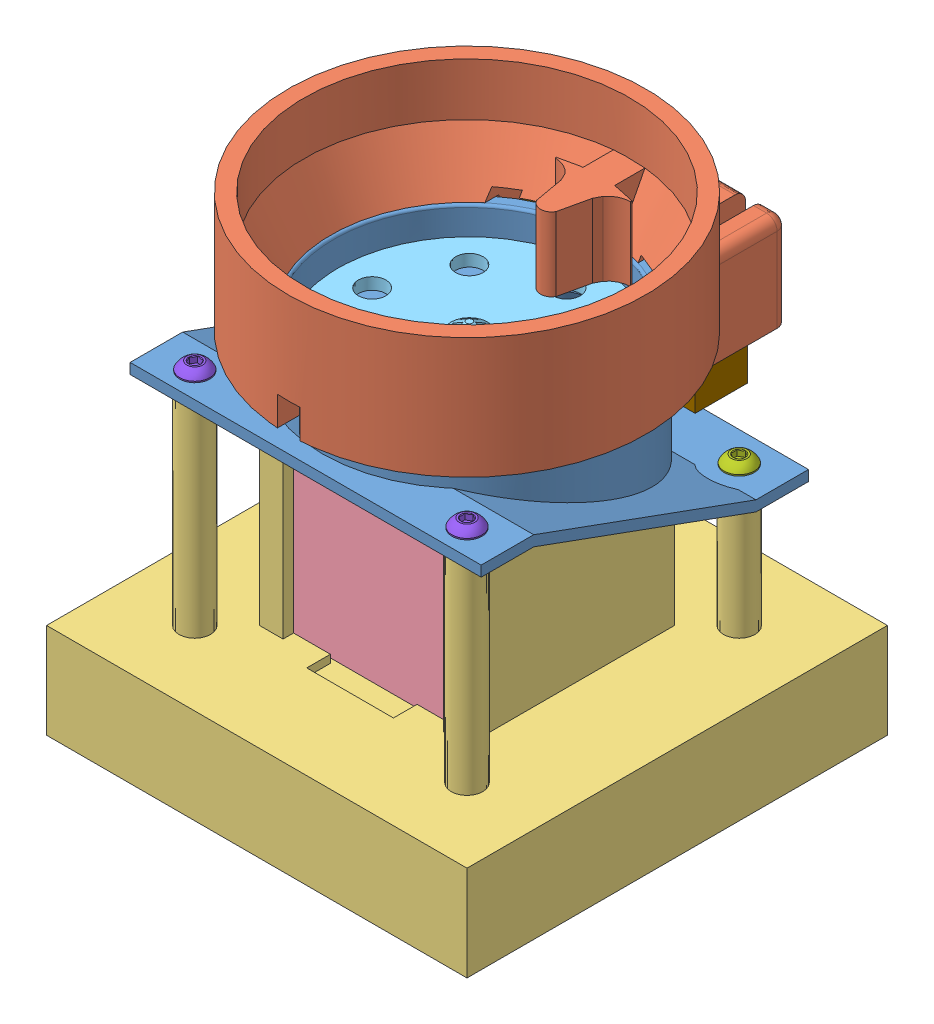
SolidWorks assembly FinalFeeder, configuration Default. Lengths in mm.
Overall size (80.53 89.55 87.61).
15 component instances, 9 part files, 34 mates.
Components (placement in the parent):
- Base V7-1: Base V7 [Default] at (6.73 27.5467 69.4591) size (66.8 28.84 76.98)
- Lid V5-1: Lid V5 [Default] at (6.73 62.8867 69.4591) x (-0.164094 0 -0.986445) z (0.986445 0 -0.164094) size (76.61 31 68.01)
- Motor Base V3-1: Motor Base V3 [Default] at (6.73 10.4376 69.4591) size (80 58.1 80)
- MotorModel-1: MotorModel [Default] at (6.73 12.9376 69.0091) size (34.6 49.4 34.6)
- Rotor V10-1: Rotor V10 [Default] at (6.73 60.8376 69.0091) x (0 0 1) z (-1 0 0) size (50 6 50)
- 90695A033 (Nut M3 thread)-1: 90695A033 (Nut M3 thread) [90695A033] at (-19.17 9.5376 95.3591) x (0.834067 0 -0.551664) z (0.551664 0 0.834067) size (5.5 2.19 6.35)
- 92095A201 (35mm lg M3 thread)-1: 92095A201 (35mm lg M3 thread) [92095A201] at (32.63 42.6967 43.5591) x (1 0 0) z (0 1 0) size (5.7 5.7 37.11)
- 92095A475 (50mm lg M3 thread)-1: 92095A475 (50mm lg M3 thread) [92095A475] at (-19.17 58.0876 95.3591) x (-0.089879 0 0.995953) z (0 1 0) size (5.7 5.7 52.2)
- 90695A033 (Nut M3 thread)-2: 90695A033 (Nut M3 thread) [90695A033] at (-19.17 9.5376 43.5591) x (0.598357 0 0.80123) z (-0.80123 0 0.598357) size (5.5 2.19 6.35)
- 92095A201 (35mm lg M3 thread)-2: 92095A201 (35mm lg M3 thread) [92095A201] at (-19.17 42.6967 43.5591) x (1 0 0) z (0 1 0) size (5.7 5.7 37.11)
- 92095A475 (50mm lg M3 thread)-2: 92095A475 (50mm lg M3 thread) [92095A475] at (32.63 58.0876 95.3591) x (1 0 0) z (0 1 0) size (5.7 5.7 52.2)
- 90695A033 (Nut M3 thread)-3: 90695A033 (Nut M3 thread) [90695A033] at (32.63 9.5376 95.3591) x (0.857215 0 -0.514959) z (0.514959 0 0.857215) size (5.5 2.19 6.35)
- 90695A033 (Nut M3 thread)-4: 90695A033 (Nut M3 thread) [90695A033] at (32.63 9.5376 43.5591) size (5.5 2.19 6.35)
- BreakBeam-1: BreakBeam [Default] at (-9.72 64.1316 32.5016) x (0 0 1) z (1 0 0) size (10 20 11)
- BreakBeam-2: BreakBeam [Default] at (23.18 64.1316 42.5016) x (0 0 -1) z (-1 0 0) size (10 20 11)
Mates (geometry in assembly coordinates):
- Coincident1: coincident anti-aligned: plane of Motor Base V3-1 through (6.73 12.9376 69.4591) normal (0 1 0); plane of MotorModel-1 through (6.73 12.9376 69.0091) normal (0 -1 0)
- Coincident3: coincident anti-aligned: plane of Motor Base V3-1 through (-11.02 12.9376 51.7091) normal (0 0 1); plane of MotorModel-1 through (-10.57 41.3376 51.7091) normal (0 0 -1)
- Concentric1: concentric aligned: cylinder of Base V7-1 through (-19.17 39.0467 43.5591) axis (0 -1 0) radius 1.75; cylinder of Motor Base V3-1 through (-19.17 54.4376 43.5591) axis (0 -1 0) radius 1.75
- Coincident4: coincident anti-aligned: plane of Base V7-1 through (40.13 54.4376 90.164) normal (0 -1 0); plane of Motor Base V3-1 through (32.63 54.4376 95.3591) normal (0 1 0)
- Concentric2: concentric aligned: cylinder of Base V7-1 through (32.63 39.0467 95.3591) axis (0 -1 0) radius 1.75; cylinder of Motor Base V3-1 through (32.63 54.4376 95.3591) axis (0 -1 0) radius 1.75
- Distance1: distance = 0.45 mm anti-aligned: plane of MotorModel-1 through (-10.57 41.3376 86.3091) normal (-1 0 0); plane of Motor Base V3-1 through (-11.02 12.9376 87.2091) normal (1 0 0)
- Parallel1: parallel aligned: plane of Lid V5-1 through (-14.27 -1.0757 29.4552) normal (0 0 -1); plane of Motor Base V3-1 through (-33.27 14.4376 29.4591) normal (0 0 -1)
- Concentric3: concentric aligned: circle of Base V7-1; circle of Lid V5-1
- Coincident8: coincident anti-aligned: plane of MotorModel-1 through (5.1052 62.3376 70.9091) normal (0 0 1); plane of Rotor V10-1 through (5.0293 70.8376 70.9091) normal (0 0 -1)
- Concentric4: concentric aligned: cylinder of MotorModel-1 through (6.73 62.3376 69.0091) axis (0 -1 0) radius 2.5; cylinder of Rotor V10-1 through (6.73 70.8376 69.0091) axis (0 -1 0) radius 2.55
- Coincident9: coincident anti-aligned: plane of MotorModel-1 through (6.73 62.3376 69.0091) normal (0 1 0); plane of Rotor V10-1 through (6.73 62.3376 69.0091) normal (0 -1 0)
- Concentric5: concentric anti-aligned: cylinder of Motor Base V3-1 through (-19.17 54.4376 95.3591) axis (0 -1 0) radius 1.75; circle of 92095A475 (50mm lg M3 thread)-1
- Concentric7: concentric aligned: circle of Motor Base V3-1; circle of 92095A475 (50mm lg M3 thread)-2
- Concentric8: concentric aligned: circle of Motor Base V3-1; circle of 92095A201 (35mm lg M3 thread)-1
- Concentric9: concentric aligned: circle of Motor Base V3-1; circle of 92095A201 (35mm lg M3 thread)-2
- Coincident12: coincident anti-aligned: plane of 92095A475 (50mm lg M3 thread)-2 through (32.63 56.4376 98.2091) normal (0 -1 0); plane of Base V7-1 through (40.13 56.4376 90.164) normal (0 1 0)
- Coincident13: coincident anti-aligned: plane of Base V7-1 through (40.13 56.4376 90.164) normal (0 1 0); plane of 92095A475 (50mm lg M3 thread)-1 through (-22.0085 56.4376 95.1029) normal (0 -1 0)
- Coincident15: coincident anti-aligned: plane of Base V7-1 through (40.13 41.0467 37.8778) normal (0 1 0); plane of 92095A201 (35mm lg M3 thread)-1 through (32.63 41.0467 46.4091) normal (0 -1 0)
- Coincident16: coincident anti-aligned: plane of Base V7-1 through (40.13 41.0467 37.8778) normal (0 1 0); plane of 92095A201 (35mm lg M3 thread)-2 through (-19.17 41.0467 46.4091) normal (0 -1 0)
- Concentric10: concentric aligned: circle of Motor Base V3-1; circle of 90695A033 (Nut M3 thread)-1
- Concentric11: concentric aligned: circle of Motor Base V3-1; circle of 90695A033 (Nut M3 thread)-2
- Concentric12: concentric aligned: circle of Motor Base V3-1; circle of 90695A033 (Nut M3 thread)-3
- Concentric13: concentric aligned: circle of Motor Base V3-1; circle of 90695A033 (Nut M3 thread)-4
- Coincident17: coincident anti-aligned: plane of Motor Base V3-1 through (6.73 10.4376 69.4591) normal (0 -1 0); plane of 90695A033 (Nut M3 thread)-4 through (29.88 10.4376 41.9714) normal (0 1 0)
- Coincident18: coincident anti-aligned: plane of Motor Base V3-1 through (6.73 10.4376 69.4591) normal (0 -1 0); plane of 90695A033 (Nut M3 thread)-2 through (-19.5433 10.4376 40.4057) normal (0 1 0)
- Coincident19: coincident anti-aligned: plane of Motor Base V3-1 through (6.73 10.4376 69.4591) normal (0 -1 0); plane of 90695A033 (Nut M3 thread)-1 through (-22.3396 10.4376 95.5519) normal (0 1 0)
- Coincident20: coincident anti-aligned: plane of Motor Base V3-1 through (6.73 10.4376 69.4591) normal (0 -1 0); plane of 90695A033 (Nut M3 thread)-3 through (29.4551 10.4376 95.4142) normal (0 1 0)
- Concentric14: concentric aligned: circle of Base V7-1; circle of BreakBeam-1
- Parallel2: parallel anti-aligned: plane of Base V7-1 through (40.13 41.0467 37.8778) normal (0 1 0); plane of BreakBeam-1 through (-1.72 44.1316 32.5016) normal (0 -1 0)
- Concentric15: concentric aligned: circle of Base V7-1; circle of BreakBeam-2
- Parallel3: parallel anti-aligned: plane of Base V7-1 through (40.13 41.0467 37.8778) normal (0 1 0); plane of BreakBeam-2 through (15.18 44.1316 42.5016) normal (0 -1 0)
- Coincident25: coincident anti-aligned: plane of Base V7-1 through (-0.77 78.2543 95.5869) normal (-1 0 0); plane of BreakBeam-1 through (-0.77 49.1316 37.5016) normal (1 0 0)
- Coincident26: coincident anti-aligned: plane of Base V7-1 through (14.23 78.2543 95.5869) normal (1 0 0); plane of BreakBeam-2 through (14.23 49.1316 37.5016) normal (-1 0 0)
- Coincident27: coincident anti-aligned: plane of Base V7-1 through (6.73 65.8867 69.4591) normal (0 1 0); plane of Lid V5-1 through (11.3247 65.8867 97.0795) normal (0 -1 0)
